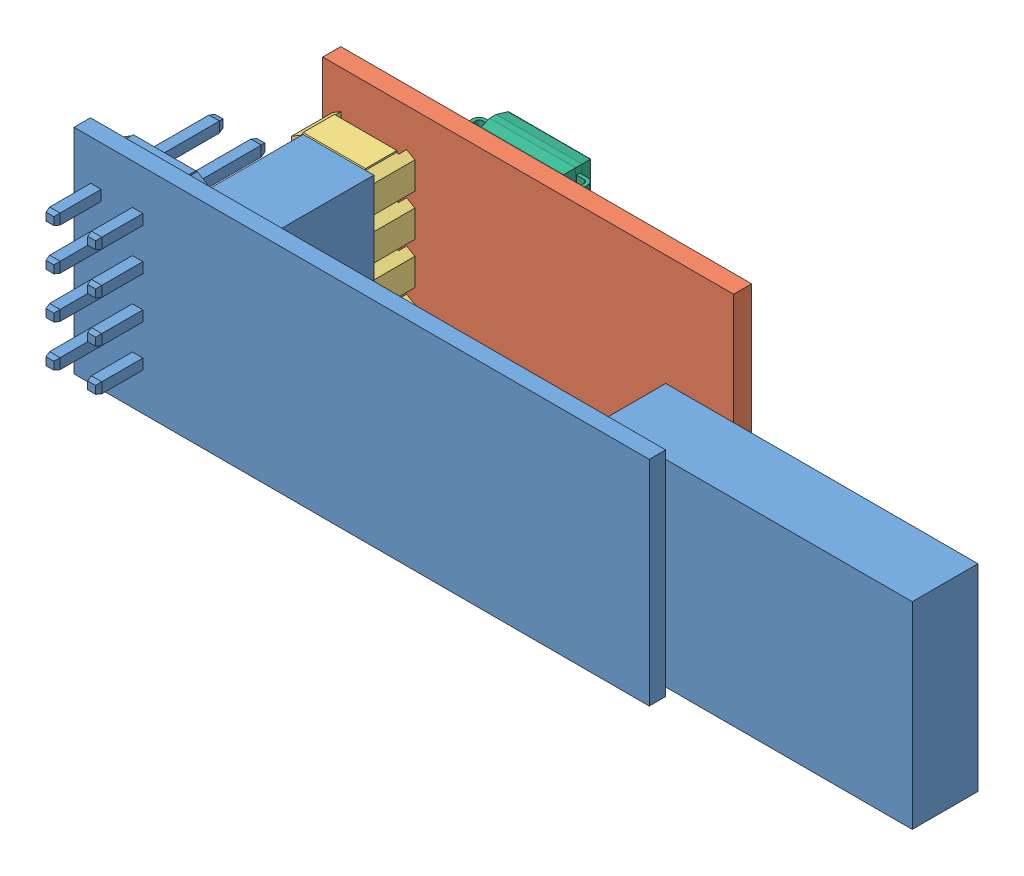
SolidWorks assembly ESP8266-ESP01_USB_Programmer, configuration Default. Lengths in mm.
Overall size (50 14.5 16.6).
16 component instances, 7 part files, 3 mates.
Components (placement in the parent):
- ESP8266-ESP01_USB_Programmer-1: ESP8266-ESP01_USB_Programmer [Default] at (-1.6523 24.1891 50.393) size (50 13 10.8)
- ESP8266-ESP01-1: ESP8266-ESP01 [Predeterminado] at (3.4865 38.7801 40.393) x (1 0 0) z (0 0 -1) size (25 14.5 10.3)
  - ESP8266-ESP01.stp-1: ESP8266-ESP01.stp [Predeterminado] at origin size (25 14.5 10.3)
    - Platine.stp-1: Platine.stp [Predeterminado] at origin size (25 14.5 1.1)
    - PinSockel.stp-1: PinSockel.stp [Predeterminado] at (1.8391 11.06 0) x (1 0 0) z (0 0 -1) size (5 10.16 2.5)
    - PCB_Antenna.stp-1: PCB_Antenna.stp [Predeterminado] at (1 16 0.81) x (0 -1 0) z (-1 0 0) size (11.4 0.04 8.67)
    - Pin_Stiftleiste.stp-1: Pin_Stiftleiste.stp [Predeterminado] at (1.8391 3.44 0) x (-1 0 0) z (0 0 -1) size (0.64 0.64 10.3)
    - Pin_Stiftleiste.stp-2: Pin_Stiftleiste.stp [Predeterminado] at (4.3791 3.44 0) x (-1 0 0) z (0 0 -1) size (0.64 0.64 10.3)
    - Pin_Stiftleiste.stp-3: Pin_Stiftleiste.stp [Predeterminado] at (1.8391 5.98 0) x (-1 0 0) z (0 0 -1) size (0.64 0.64 10.3)
    - Pin_Stiftleiste.stp-4: Pin_Stiftleiste.stp [Predeterminado] at (4.3791 5.98 0) x (-1 0 0) z (0 0 -1) size (0.64 0.64 10.3)
    - Pin_Stiftleiste.stp-5: Pin_Stiftleiste.stp [Predeterminado] at (1.8391 8.52 0) x (-1 0 0) z (0 0 -1) size (0.64 0.64 10.3)
    - Pin_Stiftleiste.stp-6: Pin_Stiftleiste.stp [Predeterminado] at (4.3791 8.52 0) x (-1 0 0) z (0 0 -1) size (0.64 0.64 10.3)
    - Pin_Stiftleiste.stp-7: Pin_Stiftleiste.stp [Predeterminado] at (1.8391 11.06 0) x (-1 0 0) z (0 0 -1) size (0.64 0.64 10.3)
    - Pin_Stiftleiste.stp-8: Pin_Stiftleiste.stp [Predeterminado] at (4.3791 11.06 0) x (-1 0 0) z (0 0 -1) size (0.64 0.64 10.3)
    - SerialFlashMem.stp-1: SerialFlashMem.stp [Predeterminado] at (8.2 0.1 1.1) size (7.9 5.23 1.97)
    - ESP8266EX.stp-1: ESP8266EX.stp [Predeterminado] at (8 6.5 1.1) size (5 5 0.95)
Mates (geometry in assembly coordinates):
- Coincident1: coincident: plane of ESP8266-ESP01_USB_Programmer-1 through (-1.6523 24.1891 42.893) normal (0 0 -1); plane of ESP8266-ESP01-1/ESP8266-ESP01.stp-1/PinSockel.stp-1 through (5.3256 27.7201 42.893) normal (0 0 1)
- Coincident2: coincident: plane of ESP8266-ESP01_USB_Programmer-1 through (4.8038 36.6101 42.893) normal (0 1 0); plane of ESP8266-ESP01-1/ESP8266-ESP01.stp-1/PinSockel.stp-1 through (8.4956 36.6101 40.393) normal (0 1 0)
- Coincident3: coincident: plane of ESP8266-ESP01_USB_Programmer-1 through (9.0956 26.3917 42.893) normal (1 0 0); plane of ESP8266-ESP01-1/ESP8266-ESP01.stp-1/PinSockel.stp-1 through (9.0956 26.8951 40.393) normal (1 0 0)
